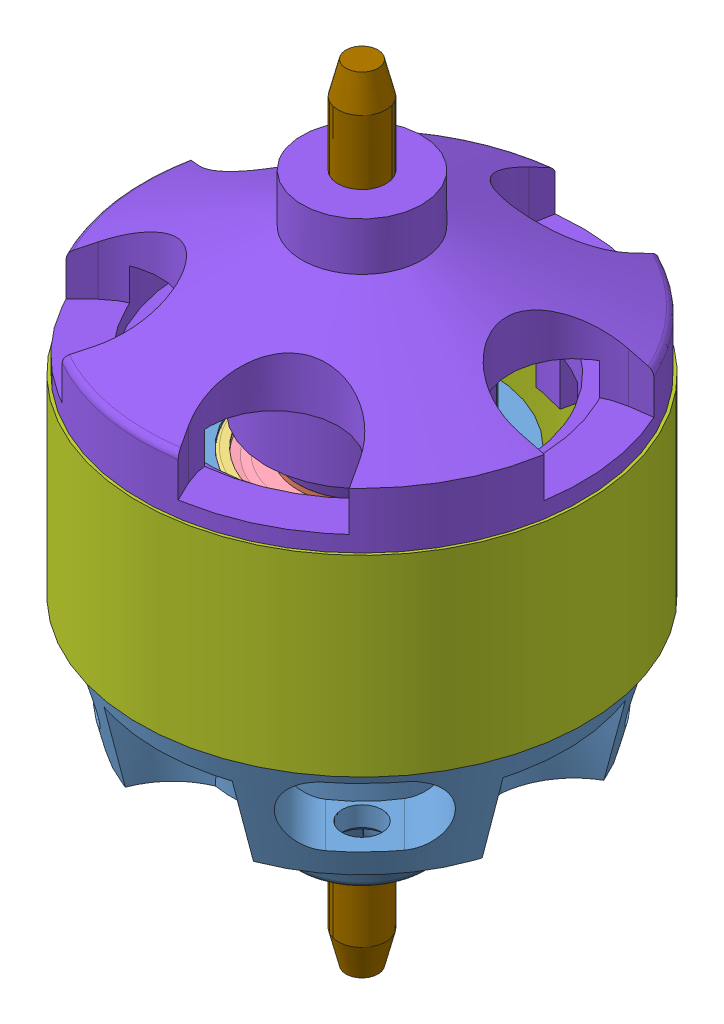
SolidWorks assembly scorpion-motor-sii-2215-1400KV, configuration Default. Lengths in mm.
Overall size (37.18 49 37.18).
31 component instances, 10 part files, 15 mates.
Components (placement in the parent):
- Winding Housing-1: Winding Housing [Default] at origin size (26.5 23.02 26.5)
- 628_6-2Z-1: 628_6-2Z [Default] x (0 1 0) z (0.590087 0 0.80734) size (5 13 13)
  - 628_6-2Z_PART1-1: 628_6-2Z_PART1 [Default] at origin size (5 7.9 7.9)
  - 628_6-2Z_PART2-1: 628_6-2Z_PART2 [Default] at origin size (5 13 13)
  - 628_6-2Z_PART3-1: 628_6-2Z_PART3 [Default] at origin size (0.24 11.7 11.7)
  - 628_6-2Z_PART4-1: 628_6-2Z_PART4 [Default] at origin size (0.15 7.26 7.26)
  - 628_6-2Z_PART5-1: 628_6-2Z_PART5 [Default] at origin size (1.98 1.98 1.98)
  - 628_6-2Z_PART5-2: 628_6-2Z_PART5 [Default] x (1 0 0) z (0 0.707107 0.707107) size (1.98 1.98 1.98)
  - 628_6-2Z_PART5-3: 628_6-2Z_PART5 [Default] x (1 0 0) z (0 1 0) size (1.98 1.98 1.98)
  - 628_6-2Z_PART5-4: 628_6-2Z_PART5 [Default] x (1 0 0) z (0 0.707107 -0.707107) size (1.98 1.98 1.98)
  - 628_6-2Z_PART5-5: 628_6-2Z_PART5 [Default] x (1 0 0) z (0 0 -1) size (1.98 1.98 1.98)
  - 628_6-2Z_PART5-6: 628_6-2Z_PART5 [Default] x (1 0 0) z (0 -0.707107 -0.707107) size (1.98 1.98 1.98)
  - 628_6-2Z_PART5-7: 628_6-2Z_PART5 [Default] x (1 0 0) z (0 -1 0) size (1.98 1.98 1.98)
  - 628_6-2Z_PART5-8: 628_6-2Z_PART5 [Default] x (1 0 0) z (0 -0.707107 0.707107) size (1.98 1.98 1.98)
- 628_6-2Z-2: 628_6-2Z [Default] at (0 15 0) x (0 -1 0) z (0 0 1) size (5 13 13)
  - 628_6-2Z_PART1-1: 628_6-2Z_PART1 [Default] at origin size (5 7.9 7.9)
  - 628_6-2Z_PART2-1: 628_6-2Z_PART2 [Default] at origin size (5 13 13)
  - 628_6-2Z_PART3-1: 628_6-2Z_PART3 [Default] at origin size (0.24 11.7 11.7)
  - 628_6-2Z_PART4-1: 628_6-2Z_PART4 [Default] at origin size (0.15 7.26 7.26)
  - 628_6-2Z_PART5-1: 628_6-2Z_PART5 [Default] at origin size (1.98 1.98 1.98)
  - 628_6-2Z_PART5-2: 628_6-2Z_PART5 [Default] x (1 0 0) z (0 0.707107 0.707107) size (1.98 1.98 1.98)
  - 628_6-2Z_PART5-3: 628_6-2Z_PART5 [Default] x (1 0 0) z (0 1 0) size (1.98 1.98 1.98)
  - 628_6-2Z_PART5-4: 628_6-2Z_PART5 [Default] x (1 0 0) z (0 0.707107 -0.707107) size (1.98 1.98 1.98)
  - 628_6-2Z_PART5-5: 628_6-2Z_PART5 [Default] x (1 0 0) z (0 0 -1) size (1.98 1.98 1.98)
  - 628_6-2Z_PART5-6: 628_6-2Z_PART5 [Default] x (1 0 0) z (0 -0.707107 -0.707107) size (1.98 1.98 1.98)
  - 628_6-2Z_PART5-7: 628_6-2Z_PART5 [Default] x (1 0 0) z (0 -1 0) size (1.98 1.98 1.98)
  - 628_6-2Z_PART5-8: 628_6-2Z_PART5 [Default] x (1 0 0) z (0 -0.707107 0.707107) size (1.98 1.98 1.98)
- Outer Casing-1: Outer Casing [Default] at (0 7 0) x (0.434234 0 0.9008) z (-0.9008 0 0.434234) size (27.85 12 27.85)
- Rotor Top-1: Rotor Top [Default] at (0 19 0) x (0.434234 0 0.9008) z (-0.9008 0 0.434234) size (27.5 16 27.55)
- Shaft-1: Shaft [Default] at (0 -13 0) x (0.959008 0 -0.283378) z (0.283378 0 0.959008) size (3 49 3)
- Shaft Collar-1: Shaft Collar [Default] at (0 -6 0) x (0.337726 0 -0.941245) z (0.941245 0 0.337726) size (8 6.5 8)
Mates (geometry in assembly coordinates):
- Coincident1: coincident aligned: plane of Winding Housing-1 through (0 0 0) normal (1 0 0); plane of assembly through (0 0 0) normal (1 0 0)
- Coincident2: coincident aligned: plane of Winding Housing-1 through (0 0 0) normal (0 0 1); plane of assembly through (0 0 0) normal (0 0 1)
- Coincident3: coincident aligned: plane of Winding Housing-1 through (0 0 0) normal (0 1 0); plane of assembly through (0 0 0) normal (0 1 0)
- Concentric1: concentric anti-aligned: cylinder of Winding Housing-1 through (0 5 0) axis (0 -1 0) radius 6.5; cylinder of 628_6-2Z-1/628_6-2Z_PART2-1 through (0 4.8 0) axis (0 1 0) radius 6.5
- Concentric2: concentric anti-aligned: cylinder of Winding Housing-1 through (0 10 0) axis (0 1 0) radius 6.5; cylinder of 628_6-2Z-2/628_6-2Z_PART2-1 through (0 10.2 0) axis (0 -1 0) radius 6.5
- Coincident5: coincident anti-aligned: plane of Winding Housing-1 through (0 10 0) normal (0 1 0); plane of 628_6-2Z-2/628_6-2Z_PART2-1 through (5.85 10 0) normal (0 -1 0)
- Coincident6: coincident anti-aligned: plane of Winding Housing-1 through (0 5 0) normal (0 -1 0); plane of 628_6-2Z-1/628_6-2Z_PART2-1 through (-4.7229 5 3.452) normal (0 1 0)
- Concentric5: concentric anti-aligned: cylinder of 628_6-2Z-2/628_6-2Z_PART1-1 through (0 10.15 0) axis (0 -1 0) radius 3; cylinder of Rotor Top-1 through (0 12.7574 0) axis (0 1 0) radius 1.5
- Coincident12: coincident anti-aligned: plane of 628_6-2Z-2/628_6-2Z_PART1-1 through (3.9 15 0) normal (0 1 0); plane of Rotor Top-1 through (0 15 0) normal (0 -1 0)
- Concentric6: concentric anti-aligned: cylinder of Rotor Top-1 through (0 12.7574 0) axis (0 1 0) radius 1.5; cylinder of Shaft-1 through (0 36 0) axis (0 -1 0) radius 1.5
- Concentric7: concentric aligned: cylinder of Shaft-1 through (0 36 0) axis (0 -1 0) radius 1.5; cylinder of Shaft Collar-1 through (0 0 0) axis (0 -1 0) radius 1.5
- Concentric8: concentric aligned: cylinder of Winding Housing-1 through (0 15 0) axis (0 -1 0) radius 8; cylinder of Outer Casing-1 through (0 19 0) axis (0 -1 0) radius 11.925
- Coincident14: coincident anti-aligned: plane of Outer Casing-1 through (0 19 0) normal (0 1 0); plane of Rotor Top-1 through (0 19 0) normal (0 -1 0)
- Coincident15: coincident aligned: circle of Shaft-1; plane of Shaft Collar-1 through (0 -6 0) normal (0 -1 0)
- Coincident16: coincident anti-aligned: plane of 628_6-2Z-1/628_6-2Z_PART1-1 through (-3.1486 0 2.3013) normal (0 -1 0); plane of Shaft Collar-1 through (0 0 0) normal (0 1 0)
